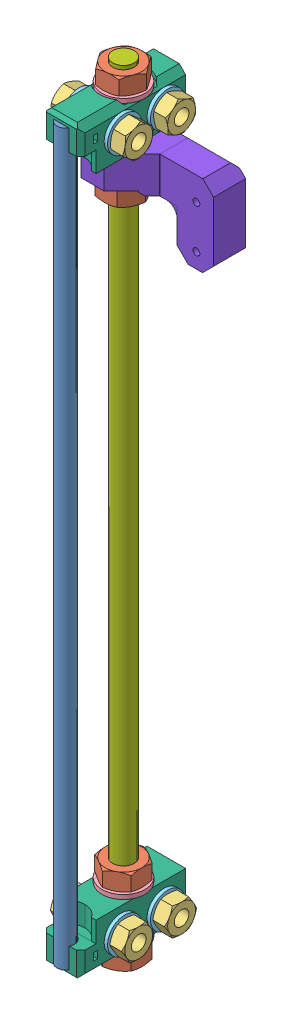
SolidWorks assembly Assembly y-axis right side, configuration Valor predeterminado. Lengths in mm.
Overall size (105.18 380.16 105.18).
31 component instances, 8 part files, 19 mates.
Components (placement in the parent):
- Smooth Rod - 8 x 340-1: Smooth Rod - 8 x 340 [Valor predeterminado] at (0 0 47) x (0.46396 0 0.885856) z (0 -1 0) size (8 8 340)
- Assembly y-corners-2: Assembly y-corners [Valor predeterminado] at (49.2679 -151.5842 11.7032) size (34.2 40 50.08)
  - Nut DIN 934 - M10-1: Nut DIN 934 - M10 [Valor predeterminado] at (-49.2679 6.8342 8.2968) x (0 -1 0) z (0.866025 0 0.5) size (8 17 19.63)
  - Nut DIN 934 - M8-1: Nut DIN 934 - M8 [Valor predeterminado] at (-63.1179 -10.1658 -1.7032) x (1 0 0) z (0 0.527567 0.849514) size (6.5 13 15.01)
  - Washer DIN 125A - M10-1: Washer DIN 125A - M10 [Valor predeterminado] at (-49.2679 -19.1658 8.2968) x (0 -1 0) z (0.326363 0 0.945245) size (2 20 20)
  - Washer DIN 125A - M8-1: Washer DIN 125A - M8 [Valor predeterminado] at (-40.2679 -10.1658 -1.7032) x (1 0 0) z (0 -0.550558 0.834797) size (1.6 16 16)
  - Washer DIN 125A - M10-2: Washer DIN 125A - M10 [Valor predeterminado] at (-49.2679 2.8342 8.2968) x (0 -1 0) z (0.326363 0 0.945245) size (2 20 20)
  - Washer DIN 125A - M8-2: Washer DIN 125A - M8 [Valor predeterminado] at (-59.8679 -10.1658 -1.7032) x (1 0 0) z (0 0.106248 0.99434) size (1.6 16 16)
  - Nut DIN 934 - M10-2: Nut DIN 934 - M10 [Valor predeterminado] at (-49.2679 -25.1658 8.2968) x (0 -1 0) z (0.866025 0 0.5) size (8 17 19.63)
  - Washer DIN 125A - M8-3: Washer DIN 125A - M8 [Valor predeterminado] at (-59.8679 -10.1658 18.2968) x (1 0 0) z (0 0.258445 0.966026) size (1.6 16 16)
  - Washer DIN 125A - M8-4: Washer DIN 125A - M8 [Valor predeterminado] at (-40.2679 -10.1658 18.2968) x (1 0 0) z (0 -0.676712 0.736248) size (1.6 16 16)
  - Nut DIN 934 - M8-2: Nut DIN 934 - M8 [Valor predeterminado] at (-63.1179 -10.1658 18.2968) x (1 0 0) z (0 0.866025 0.5) size (6.5 13 15.01)
  - Nut DIN 934 - M8-3: Nut DIN 934 - M8 [Valor predeterminado] at (-35.4179 -10.1658 18.2968) x (1 0 0) z (0 0.866025 0.5) size (6.5 13 15.01)
  - Nut DIN 934 - M8-4: Nut DIN 934 - M8 [Valor predeterminado] at (-35.4179 -10.1658 -1.7032) size (6.5 13 15.01)
  - y-corners-2: y-corners [Valor predeterminado] at (-49.2679 0.8342 -11.7032) size (18 22 49)
- Threaded Rod DIN 975 - M10 x 365-2: Threaded Rod DIN 975 - M10 x 365 [Valor predeterminado] at (0 0 20) x (0.560623 0 0.828071) z (0 1 0) size (10 10 365)
- Assembly y-corners + psu-y-part-1: Assembly y-corners + psu-y-part [Valor predeterminado] at (55.3377 186.7114 68.8965) x (-0.405972 -0.883972 0.231905) z (-0.715 0.149183 -0.683022) size (70.09 85.08 72.81)
  - Nut DIN 934 - M10-1: Nut DIN 934 - M10 [Valor predeterminado] at (19.9318 -6.7829 71.4778) x (0.883972 -0.4431 -0.149183) z (0.050052 -0.227561 0.972477) size (8 17 19.63)
  - Nut DIN 934 - M8-1: Nut DIN 934 - M8 [Valor predeterminado] at (36.4951 -12.4723 85.973) x (-0.405972 -0.569176 -0.715) z (0.913882 -0.250711 -0.319317) size (6.5 13 15.01)
  - Washer DIN 125A - M8-1: Washer DIN 125A - M8 [Valor predeterminado] at (39.1642 -1.3807 68.8448) x (0.405972 0.569176 0.715) z (-0.302013 -0.65486 0.692782) size (1.6 16 16)
  - Washer DIN 125A - M10-2: Washer DIN 125A - M10 [Valor predeterminado] at (23.4677 -8.5553 70.881) x (0.883972 -0.4431 -0.149183) z (0.236023 0.147481 0.960491) size (2 20 20)
  - Washer DIN 125A - M8-2: Washer DIN 125A - M8 [Valor predeterminado] at (35.1757 -14.3221 83.6493) x (-0.405972 -0.569176 -0.715) z (0.797091 0.162168 -0.581677) size (1.6 16 16)
  - Washer DIN 125A - M8-3: Washer DIN 125A - M8 [Valor predeterminado] at (26.5691 -26.3887 68.4913) x (0.405972 0.569176 0.715) z (-0.845418 -0.063223 0.530351) size (1.6 16 16)
  - Washer DIN 125A - M8-4: Washer DIN 125A - M8 [Valor predeterminado] at (31.8567 -11.6259 55.9748) x (-0.405972 -0.569176 -0.715) z (0.900505 -0.11575 -0.419157) size (1.6 16 16)
  - Nut DIN 934 - M8-2: Nut DIN 934 - M8 [Valor predeterminado] at (25.2496 -28.2385 66.1675) x (0.405972 0.569176 0.715) z (-0.843078 0.535209 0.05264) size (6.5 13 15.01)
  - Nut DIN 934 - M8-3: Nut DIN 934 - M8 [Valor predeterminado] at (29.8877 -14.3864 52.5071) x (-0.405972 -0.569176 -0.715) z (-0.398683 0.814303 -0.421857) size (6.5 13 15.01)
  - Nut DIN 934 - M8-4: Nut DIN 934 - M8 [Valor predeterminado] at (41.1332 1.3798 72.3126) x (0.405972 0.569176 0.715) z (-0.820941 0.570893 0.011664) size (6.5 13 15.01)
  - psu-y-part-1: psu-y-part [Valor predeterminado] at (45.8824 -41.1595 65.9269) x (-0.405972 -0.569176 -0.715) z (0.231905 0.692604 -0.683022) size (53 38 28)
  - Nut DIN 934 - M10-3: Nut DIN 934 - M10 [Valor predeterminado] at (59.7106 -26.7224 64.7645) x (0.883972 -0.4431 -0.149183) z (-0.416609 -0.601685 -0.681478) size (8 17 19.63)
  - Washer DIN 125A - M10-3: Washer DIN 125A - M10 [Valor predeterminado] at (54.4067 -24.0638 65.6596) x (0.883972 -0.4431 -0.149183) z (0.315015 0.800244 -0.51027) size (2 20 20)
  - y-corners-3: y-corners [Valor predeterminado] at (38.277 -32.1555 81.2595) x (0.405972 0.569176 0.715) z (0.231905 0.692604 -0.683022) size (18 22 49)
Mates (geometry in assembly coordinates):
- Concêntrico2: concentric: cylinder of Smooth Rod - 8 x 340-1 through (0 -170 47) axis (0 1 0) radius 4; cylinder of ? through (0 -170 47) axis (0 1 0) radius 4.2
- Coincidente3: coincident: plane of Smooth Rod - 8 x 340-1 through (0 -170 47) normal (0 -1 0); plane of ? through (0 -170 47) normal (0 1 0)
- Coincidente5: coincident: plane of assembly; plane of assembly; plane of Smooth Rod - 8 x 340-1 through (0 0 47) normal (0 -1 0); plane of Threaded Rod DIN 975 - M10 x 365-2 through (0 0 20) normal (0 1 0)
- Coincidente6: coincident: plane of Smooth Rod - 8 x 340-1 through (0 170 47) normal (0 1 0); plane of ? through (0 170 47) normal (0 -1 0)
- Concêntrico5: concentric: cylinder of Smooth Rod - 8 x 340-1 through (0 -170 47) axis (0 1 0) radius 4; cylinder of ? through (0 170 47) axis (0 -1 0) radius 4.2
- Concêntrico6: concentric: cylinder of ? through (0 -177.75 20) axis (0 1 0) radius 5.4; cylinder of Threaded Rod DIN 975 - M10 x 365-2 through (0 182.5 20) axis (0 -1 0) radius 5
- Coincidente7: coincident: plane of ? through (-9 -172.75 0) normal (0 0 -1); plane of ? through (9 172.75 0) normal (0 0 -1)
- Coincidente8: coincident: plane of ? through (9 172.75 0) normal (0 0 -1); plane of assembly through (0 0 0) normal (0 0 1)
- Coincidente9: coincident: line of assembly; line of Smooth Rod - 8 x 340-1 through (0 -170 47) axis (0 1 0); plane of assembly
- Coincidente10: coincident: plane of assembly through (0 0 0) normal (0 1 0); plane of Smooth Rod - 8 x 340-1 through (0 0 47) normal (0 -1 0); plane of assembly
- Concêntrico7: concentric: cylinder of assembly; cylinder of assembly; cylinder of Smooth Rod - 8 x 340-1 through (0 -170 47) axis (0 1 0) radius 4; cylinder of Assembly y-corners-2/y-corners-2 through (0 -170 47) axis (0 1 0) radius 4.2
- Coincidente11: coincident: plane of assembly; plane of assembly; plane of Smooth Rod - 8 x 340-1 through (0 -170 47) normal (0 -1 0); plane of Assembly y-corners-2/y-corners-2 through (0 -170 47) normal (0 1 0)
- Concêntrico8: concentric: cylinder of assembly; cylinder of assembly; cylinder of Assembly y-corners-2/Nut DIN 934 - M10-2 through (0 -180.75 20) axis (0 1 0) radius 4.25; cylinder of Threaded Rod DIN 975 - M10 x 365-2 through (0 182.5 20) axis (0 -1 0) radius 5
- Coincidente13: coincident: plane of assembly; plane of Assembly y-corners-2/y-corners-2 through (0 -150.75 0) normal (1 0 0); plane of assembly
- Coincidente14: coincident: plane of assembly; plane of Assembly y-corners-2/y-corners-2 through (-9 -172.75 0) normal (0 0 -1); plane of assembly
- Coincidente16: coincident: plane of assembly; plane of assembly; plane of Smooth Rod - 8 x 340-1 through (0 -170 47) normal (0 -1 0); plane of Assembly y-corners-2/y-corners-2 through (0 -170 47) normal (0 1 0)
- Concêntrico9: concentric: cylinder of assembly; cylinder of assembly; cylinder of Smooth Rod - 8 x 340-1 through (0 -170 47) axis (0 1 0) radius 4; cylinder of Assembly y-corners + psu-y-part-1/y-corners-3 through (0 170 47) axis (0 -1 0) radius 4.2
- Coincidente17: coincident: plane of assembly; plane of assembly; plane of Smooth Rod - 8 x 340-1 through (0 170 47) normal (0 1 0); plane of Assembly y-corners + psu-y-part-1/y-corners-3 through (0 170 47) normal (0 -1 0)
- Coincidente18: coincident: plane of assembly; plane of Assembly y-corners + psu-y-part-1/y-corners-3 through (0 150.75 0) normal (-1 0 0); plane of assembly
